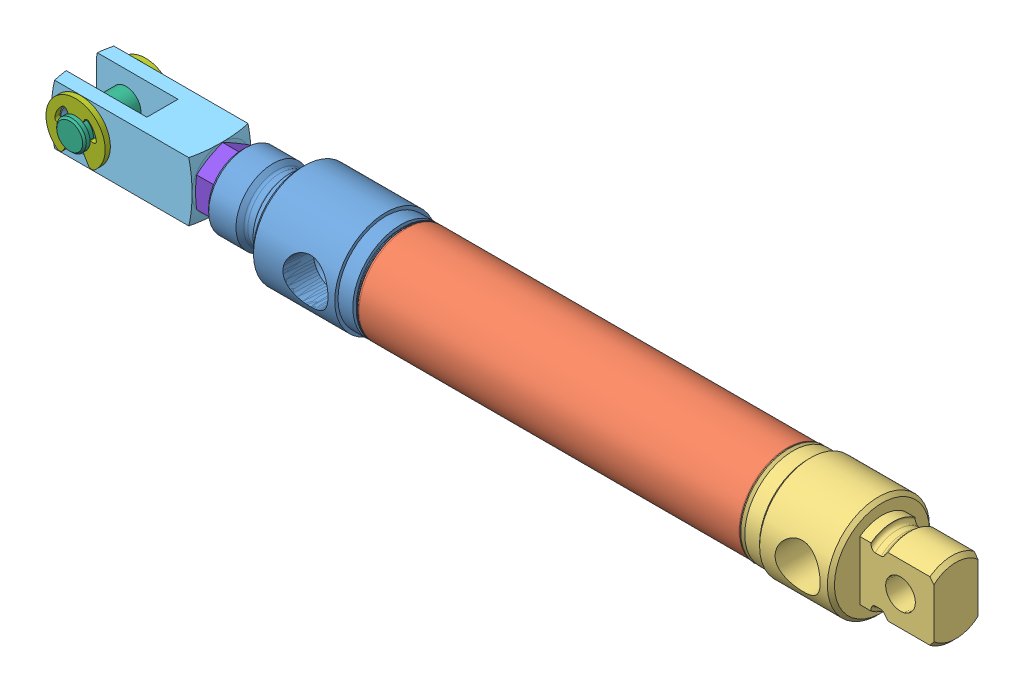
SolidWorks assembly 042-DP(F,D-166-3), configuration Default. Lengths in mm.
Overall size (188.56 24.42 24.42).
12 component instances, 10 part files, 17 mates.
Components (placement in the parent):
- 042-DPC(F,D-166-3)0000_0_dummy-1: 042-DPC(F,D-166-3)0000_0_dummy [Default] at origin
- 04R000-0_rod_guide-1: 04R000-0_rod_guide [Default] at origin size (40.49 21.91 21.91)
- 04R-3_25550C-1: 04R-3_25550C [Default] at (34.8361 0 0) size (84.04 20.51 20.51)
- 04P0000_rear_head-1: 04P0000_rear_head [Default] at (112.7252 0 0) size (40.49 21.91 21.91)
- C-042-DP0_rod-1: C-042-DP0_rod [Default] x (1 0 0) z (0 -0.322348 0.946621) size (125.43 19.24 19.24)
- D-166-3-dummy-1: D-166-3-dummy [Default] at (-27.8892 0 0) x (1 0 0) z (0 -0.322348 0.946621)
- Bimba D-166-3-1: Bimba D-166-3 [Default] at (-28.1432 0 0) size (35.1 12.9 17.53)
  - _D-14055-1: _D-14055 [Default] x (1 0 0) z (0 0 -1) size (31.89 12.7 12.7)
  - _D-8381-1: _D-8381 [Default] x (0 0 1) z (-1 0 0) size (17.53 6.35 6.35)
  - _D-5866-1: _D-5866 [Default] at (0 0 6.9533) x (-1 0 0) z (0 0 -1) size (12.7 11.45 1.1)
  - _D-5866-2: _D-5866 [Default] at (0 0 -6.9533) x (-1 0 0) z (0 0 -1) size (12.7 11.45 1.1)
  - _D-344-1: _D-344 [Default] at (23.8252 0 0) x (0 0 1) z (-1 0 0) size (11.18 12.9 4.06)
Mates (geometry in assembly coordinates):
- Distance2: distance = 0 mm aligned: plane of 04R000-0_rod_guide-1 through (0 0 0) normal (1 0 0); plane of 042-DPC(F,D-166-3)0000_0_dummy-1 through (0 0 0) normal (1 0 0)
- Coincident1: coincident aligned: line of 042-DPC(F,D-166-3)0000_0_dummy-1 through (80.9 0 0) axis (-1 0 0); line of 04R000-0_rod_guide-1 through (80.9 0 0) axis (-1 0 0)
- Angle3: planar angle = 0 rad aligned: plane of 04R000-0_rod_guide-1 through (0 0 0) normal (0 0 -1); plane of 042-DPC(F,D-166-3)0000_0_dummy-1 through (0 0 0) normal (0 0 -1)
- Distance4: distance = 0 mm aligned: plane of 04R-3_25550C-1 through (34.8361 0 0) normal (1 0 0); plane of 04R000-0_rod_guide-1 through (34.8361 0 0) normal (1 0 0)
- Coincident2: coincident aligned: line of 04R000-0_rod_guide-1 through (80.9 0 0) axis (-1 0 0); line of 04R-3_25550C-1 through (115.7361 0 0) axis (-1 0 0)
- Angle6: planar angle = 0 rad aligned: plane of 04R-3_25550C-1 through (34.8361 0 0) normal (0 0 -1); plane of 04R000-0_rod_guide-1 through (0 0 0) normal (0 0 -1)
- Distance6: distance = 0 mm aligned: plane of 04P0000_rear_head-1 through (117.5258 0 0) normal (1 0 0); plane of 04R-3_25550C-1 through (117.5258 0 0) normal (1 0 0)
- Coincident3: coincident aligned: line of 04R-3_25550C-1 through (115.7361 0 0) axis (-1 0 0); line of 04P0000_rear_head-1 through (193.6252 0 0) axis (-1 0 0)
- Angle9: planar angle = 0.000031 rad aligned: plane of 04P0000_rear_head-1 through (112.7252 0 0) normal (0 0 -1); plane of 04R-3_25550C-1 through (34.8361 0 0) normal (0 0 -1)
- LimitDistance2: limit distance = 0 mm aligned: plane of C-042-DP0_rod-1; plane of 04R000-0_rod_guide-1 through (0 0 0) normal (1 0 0)
- Coincident5: coincident aligned: line of 04R000-0_rod_guide-1 through (80.9 0 0) axis (-1 0 0); line of C-042-DP0_rod-1 through (80.9 0 0) axis (-1 0 0)
- Distance9: distance = 0 mm aligned: plane of D-166-3-dummy-1; plane of C-042-DP0_rod-1
- Coincident6: coincident aligned: line of C-042-DP0_rod-1 through (80.9 0 0) axis (-1 0 0); line of D-166-3-dummy-1 through (53.0108 0 0) axis (-1 0 0)
- Angle15: planar angle = 0 rad aligned: plane of D-166-3-dummy-1; plane of C-042-DP0_rod-1
- Parallel1: parallel aligned: plane of 04P0000_rear_head-1 through (137.3378 21.9075 4.7307) normal (0 0 1); plane of Bimba D-166-3-1/_D-14055-1 through (-28.1432 0 6.35) normal (0 0 1)
- Coincident8: coincident aligned: cylinder of C-042-DP0_rod-1 through (112.7252 0 0) axis (-1 0 0) radius 3.175; circle of Bimba D-166-3-1/_D-344-1
- Coincident10: coincident aligned: plane of C-042-DP0_rod-1 through (-0.254 3.246 1.1053) normal (1 0 0); plane of Bimba D-166-3-1/_D-344-1 through (-0.254 5.588 0) normal (1 0 0)
